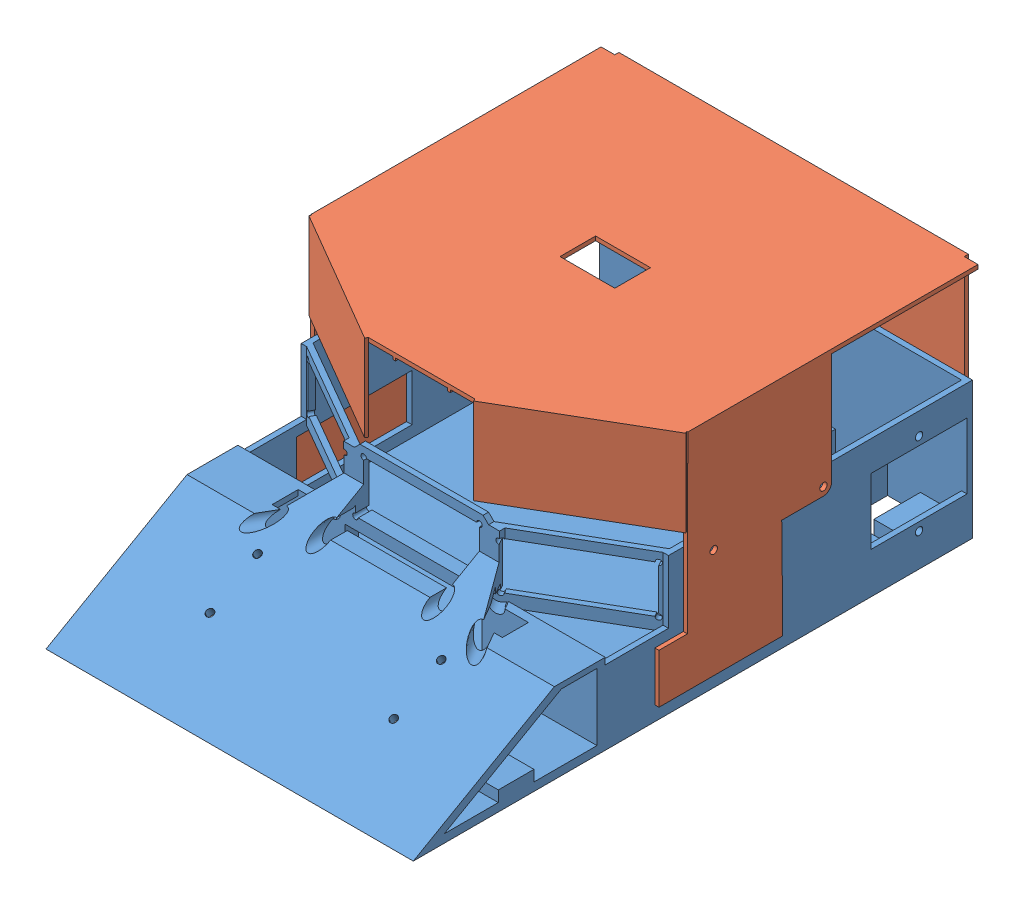
SolidWorks assembly Assem1, configuration Default. Lengths in mm.
Overall size (137.51 87 206).
2 component instances, 2 part files, 2 mates.
Components (placement in the parent):
- drivebase - demo2-1: drivebase - demo2 [Default] at (78.186 86.6307 116.3185) size (134 52 204)
- lid-2: lid [Default] at (77.936 173.6307 116.0664) x (1 0 0) z (0 0 -1) size (137.51 81.7 136.61)
Mates (geometry in assembly coordinates):
- Concentric1: concentric: cylinder of drivebase - demo2-1 through (7.3676 131.6307 145.2164) axis (1 0 0) radius 1.35; cylinder of lid-2 through (150.5044 131.6307 145.2164) axis (-1 0 0) radius 1.35
- Coincident1: coincident: plane of drivebase - demo2-1 through (145.186 136.6307 49.3185) normal (1 0 0); plane of lid-2 through (145.186 128.6307 116.0664) normal (-1 0 0)
